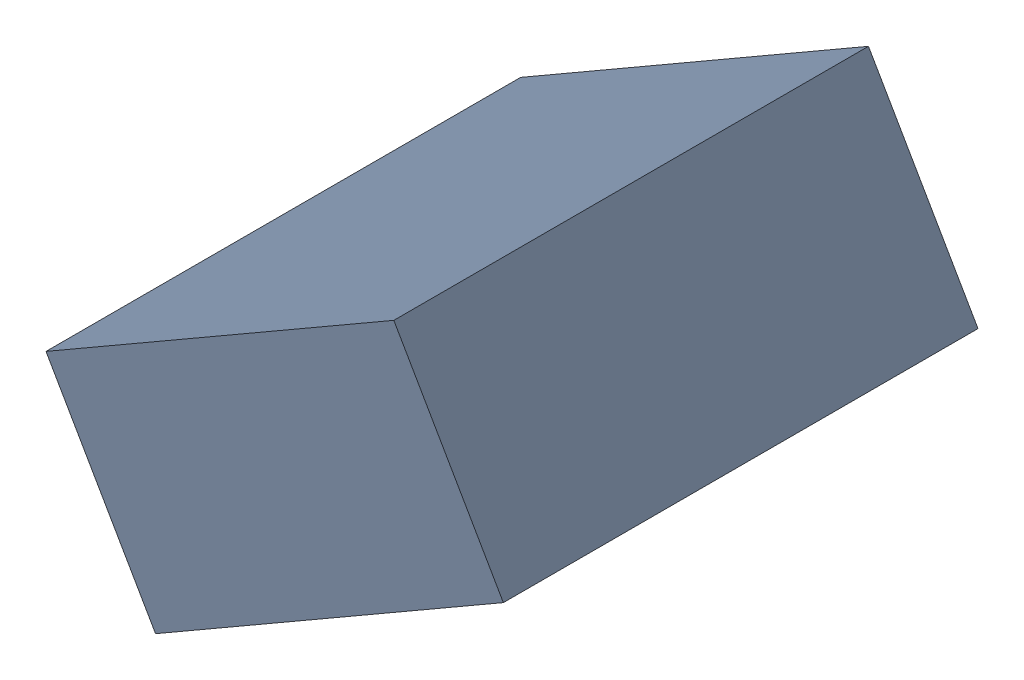
SolidWorks assembly C23_TDA2, configuration Standard. Lengths in mm.
Overall size (1.25 1.07 1.3).
2 component instances, 1 part files, 0 mates.
Components (placement in the parent):
- 885542920-1: 885542920 [Standard] at (45.1169 24.0504 0) size (1.25 1.07 1.3)
  - Extruded_24-1: Extruded_24 [Standard] at origin size (1.25 1.07 1.3)
